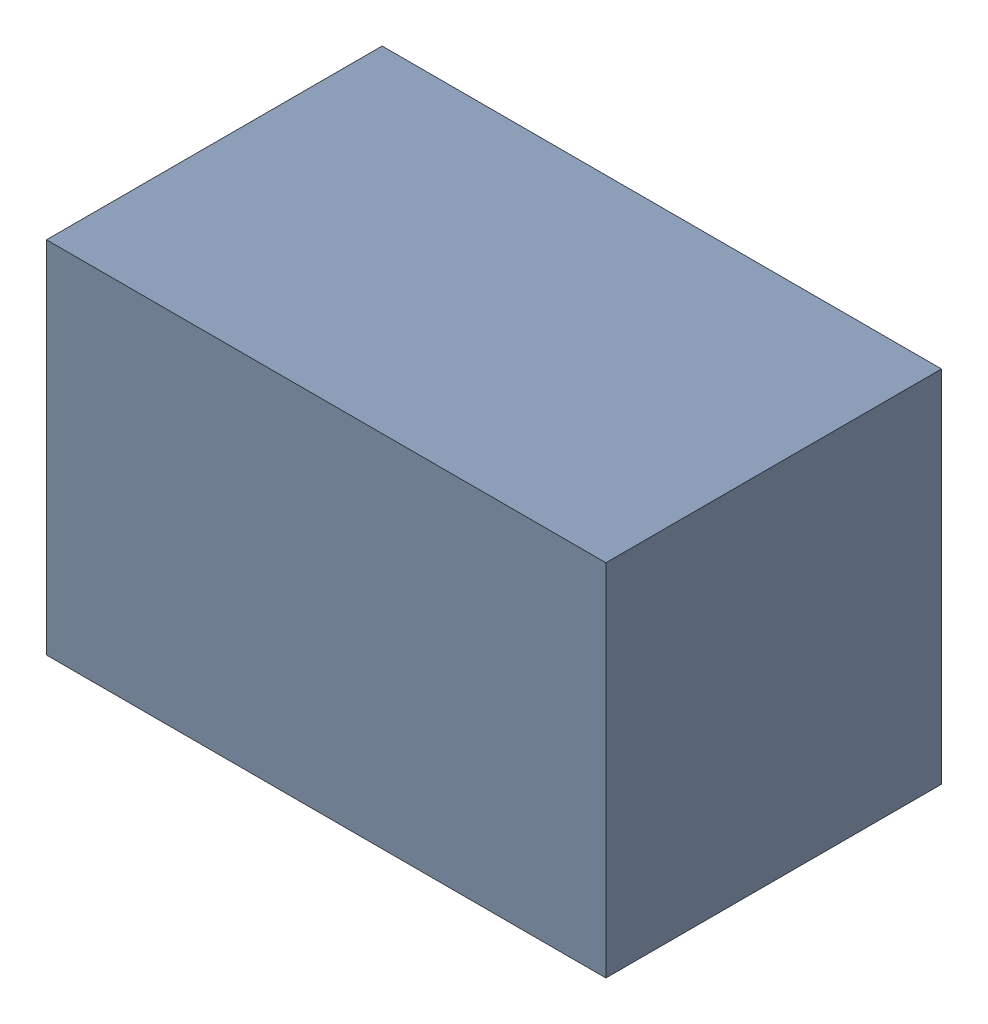
SolidWorks assembly C12, configuration Default. Lengths in mm.
Overall size (2.1 1.35 1.26).
2 component instances, 1 part files, 0 mates.
Components (placement in the parent):
- 407985824-1: 407985824 [Default] at (50.419 68.326 0.0127) size (2.1 1.35 1.26)
  - Extruded_2-1: Extruded_2 [Default] at origin size (2.1 1.35 1.26)
